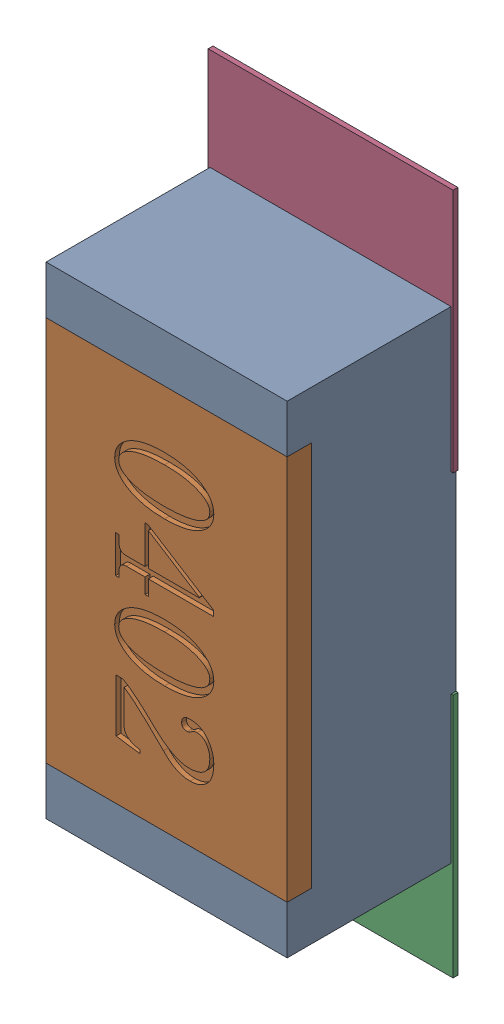
SolidWorks assembly R66, configuration Défaut. Lengths in mm.
Overall size (0.51 1.42 0.35).
5 component instances, 2 part files, 0 mates.
Components (placement in the parent):
- R0402-1: R0402 [Défaut] at (41.9776 -32.3106 0) x (0 -1 0) z (0 0 1) size (1 0.5 0.35)
- 6504207776-1: 6504207776 [Défaut] at (41.9778 -32.7606 0) size (0.51 0.51 0.01)
  - Extruded-1: Extruded [Défaut] at origin size (0.51 0.51 0.01)
- 6504207776-2: 6504207776 [Défaut] at (41.9778 -31.8535 0) size (0.51 0.51 0.01)
  - Extruded-1: Extruded [Défaut] at origin size (0.51 0.51 0.01)
